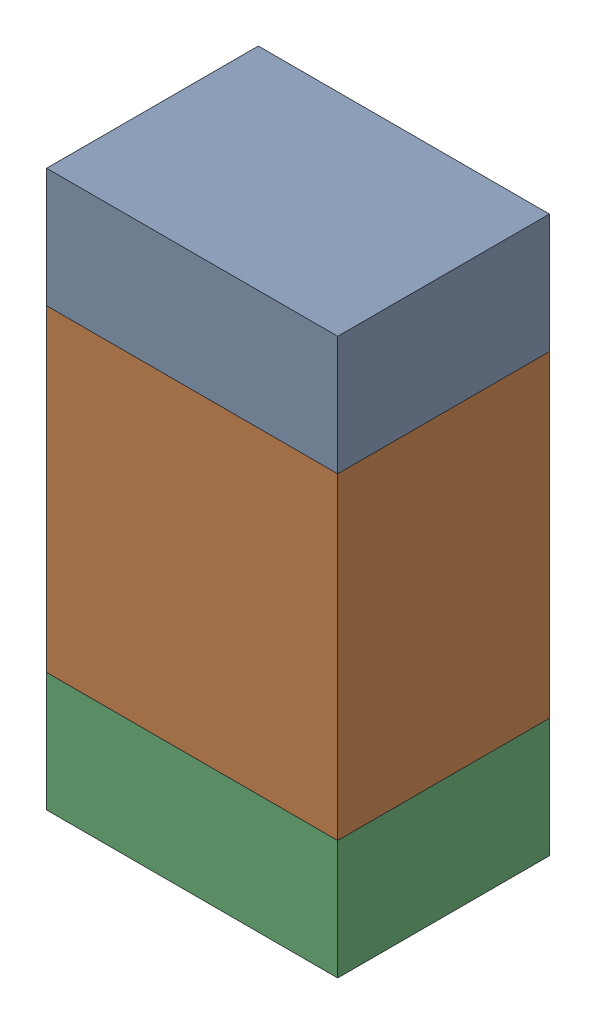
SolidWorks assembly R104_2PCB, configuration Default. Lengths in mm.
Overall size (0.55 1.05 0.4).
6 component instances, 2 part files, 0 mates.
Components (placement in the parent):
- 846483288-1: 846483288 [Default] at (117.6001 92.4124 0) size (0.55 0.22 0.4)
  - Extruded_12-1: Extruded_12 [Default] at origin size (0.55 0.22 0.4)
- 846483424-1: 846483424 [Default] at (117.6001 91.9999 0) size (0.55 0.6 0.4)
  - Extruded_13-1: Extruded_13 [Default] at origin size (0.55 0.6 0.4)
- 846483288-2: 846483288 [Default] at (117.6001 91.5874 0) size (0.55 0.22 0.4)
  - Extruded_12-1: Extruded_12 [Default] at origin size (0.55 0.22 0.4)
